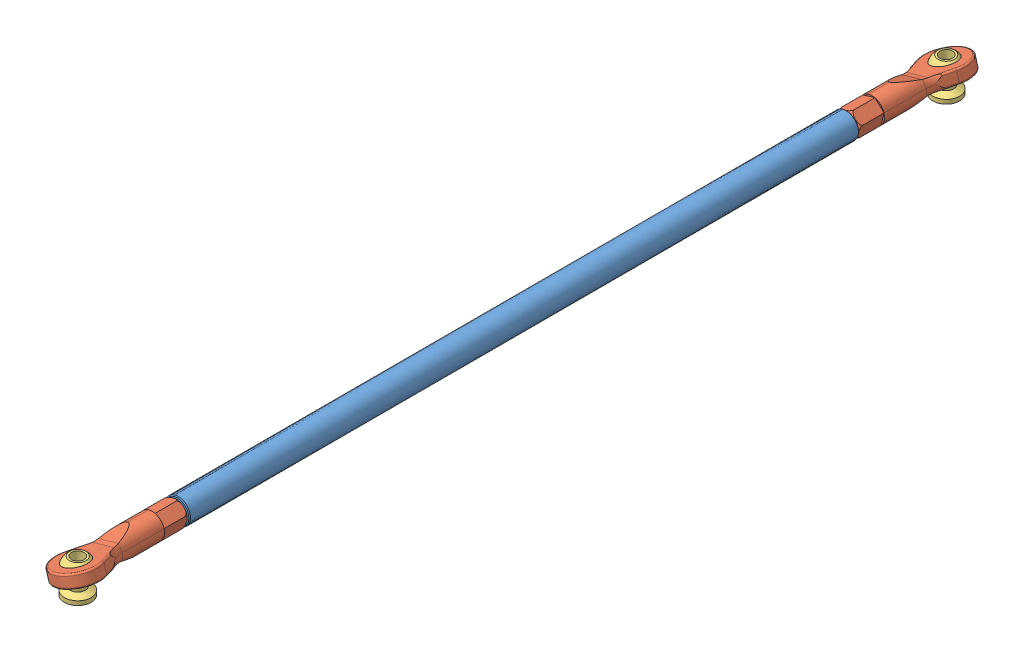
SolidWorks assembly ConnectingRods, configuration 默认. Lengths in mm.
Overall size (11.76 9.75 218).
5 component instances, 3 part files, 7 mates.
Components (placement in the parent):
- ConnectingRods-1: ConnectingRods [默认] at (-5.4112 -12.0755 162.8238) size (6 6 160)
- 球头扣-1: 球头扣 [Default] at (-1.693 -14.1188 162.8238) x (0 0 -1) z (0.960251 0.279137 0) size (29 6 10.5)
- 球头扣-2: 球头扣 [Default] at (-7.4545 -15.7936 322.8238) x (0 0 1) z (-0.960251 -0.279137 0) size (29 6 10.5)
- 球头-1: 球头 [Default] at (-5.4112 -17.4755 139.0738) size (6.5 8 6.5)
- 球头-2: 球头 [Default] at (-5.4112 -17.4755 346.5738) size (6.5 8 6.5)
Mates (geometry in assembly coordinates):
- Concentric1: concentric anti-aligned: cylinder of ConnectingRods-1 through (-5.4112 -12.0755 174.8238) axis (0 0 -1) radius 1.2; cylinder of 球头扣-1 through (-5.4112 -12.0755 152.8238) axis (0 0 1) radius 1.25
- Coincident1: coincident anti-aligned: plane of ConnectingRods-1 through (-5.4112 -12.0755 162.8238) normal (0 0 -1); plane of 球头扣-1 through (-3.3678 -8.3573 162.8238) normal (0 0 1)
- Concentric2: concentric anti-aligned: cylinder of ConnectingRods-1 through (-5.4112 -12.0755 310.8238) axis (0 0 1) radius 1.2; cylinder of 球头扣-2 through (-5.4112 -12.0755 332.8238) axis (0 0 -1) radius 1.25
- Coincident2: coincident anti-aligned: plane of ConnectingRods-1 through (-5.4112 -12.0755 322.8238) normal (0 0 1); plane of 球头扣-2 through (-9.1293 -10.0321 322.8238) normal (0 0 -1)
- Coincident3: coincident aligned: plane of 球头扣-1 through (-0.0684 -8.9603 146.2258) normal (-0.279137 0.960251 0); plane of 球头扣-2 through (-11.5914 -12.3099 339.4219) normal (-0.279137 0.960251 0)
- Concentric3: concentric: sphere of 球头-1; sphere of 球头扣-1
- Concentric4: concentric: sphere of 球头扣-2; sphere of 球头-2
